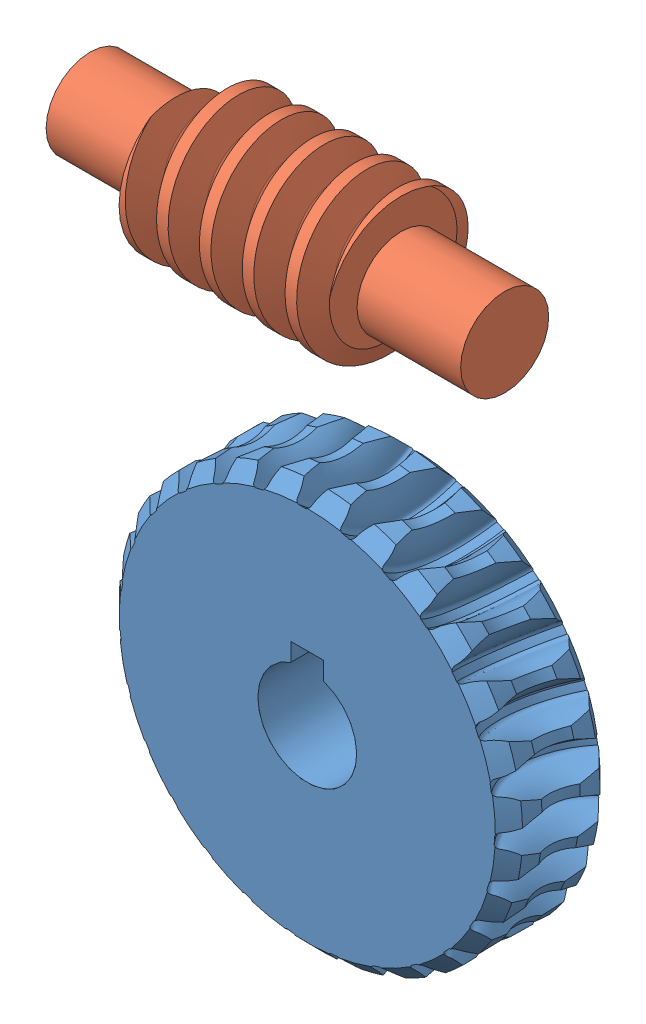
SolidWorks assembly 装配体2, configuration 默认. Lengths in mm.
Overall size (95.19 114.76 32.34).
2 component instances, 2 part files, 0 mates.
Components (placement in the parent):
- 示例蜗轮-1: 示例蜗轮 [默认] at (10.8533 -34.3983 95.3476) size (77.41 95.2 22.69)
- 示例蜗杆-1: 示例蜗杆 [默认] at (-26.6328 27.8918 88.2576) size (95 27.41 28.11)
